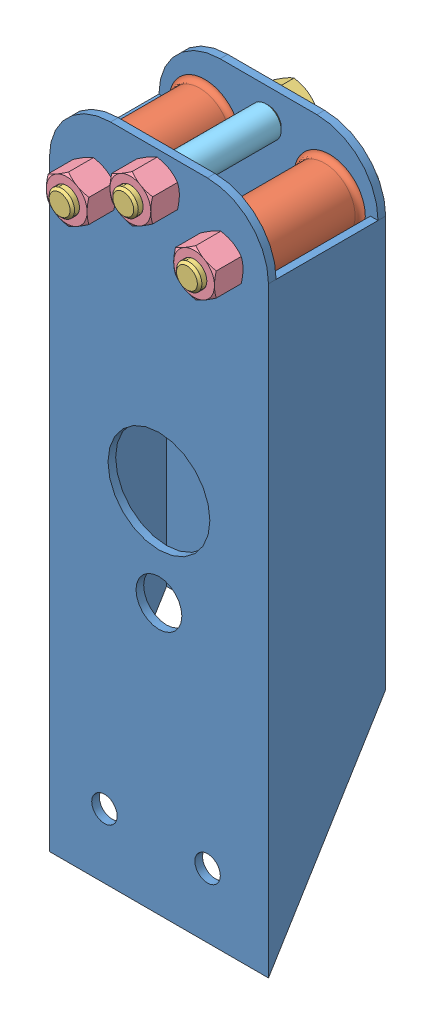
SolidWorks assembly main-block-assembly, configuration Défaut. Lengths in mm.
Overall size (43.46 130 33.88).
10 component instances, 5 part files, 18 mates.
Components (placement in the parent):
- main-block-1: main-block [Défaut] at origin size (43 130 23)
- roller-1: roller [Défaut] at (30.2861 36.874 -20.1586) x (0 0 1) z (-0.883544 -0.468348 0) size (19.5 14 14)
- roller-2: roller [Défaut] at (8.655 37.5394 -20.6586) x (0 0 1) z (-0.995256 0.097287 0) size (19.5 14 14)
- hex screw gradec_iso-2: hex screw gradec_iso [ISO 4018 - M5 x 30-WN] at (8.0756 31.6117 -3.875) x (0 0 1) z (-1 0 0) size (33.88 9.24 8)
- hex screw gradec_iso-3: hex screw gradec_iso [ISO 4018 - M5 x 30-WN] at (33.0756 31.6117 -3.875) x (0 0 1) z (-1 0 0) size (33.88 9.24 8)
- hex nut gradec_iso-1: hex nut gradec_iso [Hexagon Nut ISO - 4034 - M5 - N] at (8.0756 31.6117 28.6) size (8 9.24 5.6)
- hex nut gradec_iso-2: hex nut gradec_iso [Hexagon Nut ISO - 4034 - M5 - N] at (33.0756 31.6117 28.6) size (8 9.24 5.6)
- central-roller-1: central-roller [Défaut] at (20.5756 37.9524 2) x (0.29941 -0.954125 0) z (0 0 1) size (6 6 19.5)
- hex screw gradec_iso-4: hex screw gradec_iso [ISO 4018 - M5 x 30-WN] at (20.5756 37.9524 -3.875) x (0 0 1) z (-1 0 0) size (33.88 9.24 8)
- hex nut gradec_iso-3: hex nut gradec_iso [Hexagon Nut ISO - 4034 - M5 - N] at (20.5756 37.9524 28.6) size (8 9.24 5.6)
Mates (geometry in assembly coordinates):
- Coaxiale1: concentric anti-aligned: cylinder of main-block-1 through (33.0756 31.6117 23) axis (0 0 -1) radius 2.5; cylinder of roller-1 through (33.0756 31.6117 2) axis (0 0 1) radius 2.5
- Coïncidente2: coincident anti-aligned: plane of main-block-1 through (0.5756 -86.3883 21.5) normal (0 0 -1); plane of roller-1 through (41.8867 14.9895 21.5) normal (0 0 1)
- Coaxiale2: concentric anti-aligned: cylinder of main-block-1 through (8.0756 31.6117 23) axis (0 0 -1) radius 2.5; cylinder of roller-2 through (8.0756 31.6117 1.5) axis (0 0 1) radius 2.5
- Coïncidente3: coincident anti-aligned: plane of main-block-1 through (0.5756 -86.3883 1.5) normal (0 0 1); plane of roller-2 through (6.2453 12.8878 1.5) normal (0 0 -1)
- Coaxiale3: concentric aligned: cylinder of main-block-1 through (8.0756 31.6117 23) axis (0 0 -1) radius 2.5; cylinder of hex screw gradec_iso-2 through (8.0756 31.6117 -3.875) axis (0 0 -1) radius 2.5
- Coïncidente4: coincident anti-aligned: plane of main-block-1 through (11.0756 31.6117 0) normal (0 0 -1); plane of hex screw gradec_iso-2 through (8.0756 36.2305 0) normal (0 0 1)
- Coaxiale4: concentric aligned: cylinder of main-block-1 through (33.0756 31.6117 23) axis (0 0 -1) radius 2.5; cylinder of hex screw gradec_iso-3 through (33.0756 31.6117 -3.875) axis (0 0 -1) radius 2.5
- Coïncidente5: coincident anti-aligned: plane of main-block-1 through (11.0756 31.6117 0) normal (0 0 -1); plane of hex screw gradec_iso-3 through (33.0756 36.2305 0) normal (0 0 1)
- Coaxiale5: concentric anti-aligned: cylinder of hex screw gradec_iso-2 through (8.0756 31.6117 -3.875) axis (0 0 -1) radius 2.5; cylinder of hex nut gradec_iso-1 through (8.0756 31.6117 3.5625) axis (0 0 1) radius 2.5
- Coïncidente6: coincident anti-aligned: plane of main-block-1 through (11.0756 31.6117 23) normal (0 0 1); plane of hex nut gradec_iso-1 through (8.0756 36.2305 23) normal (0 0 -1)
- Coaxiale6: concentric anti-aligned: cylinder of hex screw gradec_iso-3 through (33.0756 31.6117 -3.875) axis (0 0 -1) radius 2.5; cylinder of hex nut gradec_iso-2 through (33.0756 31.6117 3.5625) axis (0 0 1) radius 2.5
- Coïncidente7: coincident anti-aligned: plane of main-block-1 through (11.0756 31.6117 23) normal (0 0 1); plane of hex nut gradec_iso-2 through (33.0756 36.2305 23) normal (0 0 -1)
- Coaxiale7: concentric aligned: cylinder of main-block-1 through (20.5756 37.9524 23) axis (0 0 -1) radius 2.5; cylinder of central-roller-1 through (20.5756 37.9524 21.5) axis (0 0 -1) radius 2.5
- Coïncidente8: coincident anti-aligned: plane of main-block-1 through (0.5756 -86.3883 21.5) normal (0 0 -1); plane of central-roller-1 through (20.5756 37.9524 21.5) normal (0 0 1)
- Coaxiale8: concentric aligned: cylinder of main-block-1 through (20.5756 37.9524 23) axis (0 0 -1) radius 2.5; cylinder of hex screw gradec_iso-4 through (20.5756 37.9524 -3.875) axis (0 0 -1) radius 2.5
- Coïncidente9: coincident anti-aligned: plane of main-block-1 through (11.0756 31.6117 0) normal (0 0 -1); plane of hex screw gradec_iso-4 through (20.5756 42.5712 0) normal (0 0 1)
- Coaxiale9: concentric anti-aligned: cylinder of hex screw gradec_iso-4 through (20.5756 37.9524 -3.875) axis (0 0 -1) radius 2.5; cylinder of hex nut gradec_iso-3 through (20.5756 37.9524 3.5625) axis (0 0 1) radius 2.5
- Coïncidente10: coincident anti-aligned: plane of main-block-1 through (11.0756 31.6117 23) normal (0 0 1); plane of hex nut gradec_iso-3 through (20.5756 42.5712 23) normal (0 0 -1)
